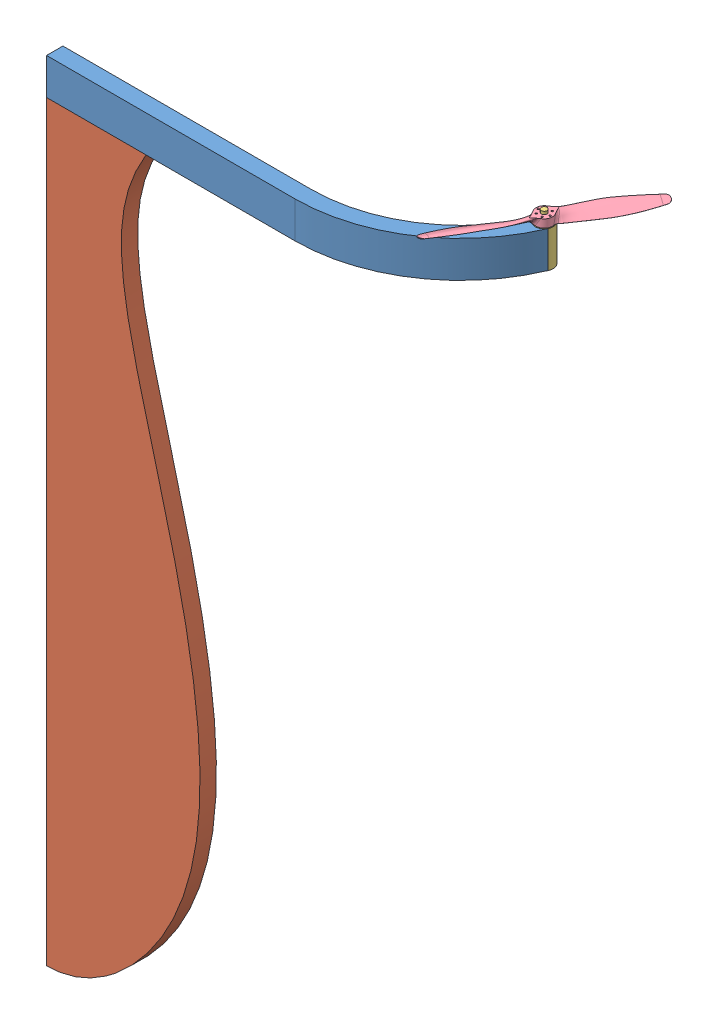
SolidWorks assembly sym, configuration Default. Lengths in mm.
Overall size (867.99 256.75 952.37).
6 component instances, 4 part files, 2 mates.
Components (placement in the parent):
- bodysym-1: bodysym [Default] at (-16.2495 216.5456 2.6479) size (110.04 216.55 28.06)
  - mp-1: mp [Default] at (9.9204 70.4329 1.4803) size (110.04 10 28.06)
  - plade 2-1: plade 2 [Default] at (-8.8992 -21.1842 13.0421) x (0 -1 0) z (0 0 -1) size (206.55 46.77 4.49)
- motorsym-1: motorsym [Default] at (69.1428 286.9784 -66.2088) x (-0.6324 0 0.774642) z (-0.774642 0 -0.6324) size (950.73 131.02 344.34)
  - motor-1: motor [Default] at (56.1749 10 -15.5304) x (-0.204409 0 -0.978885) z (0.978885 0 -0.204409) size (4.92 13 4.92)
  - propeller-1: propeller [Default] at (54.4283 1.9853 -17.262) x (0.987389 0 -0.158315) z (0.158315 0 0.987389) size (939.94 131.02 198.03)
Mates (geometry in assembly coordinates):
- Concentric2: concentric anti-aligned: cylinder of bodysym-1/mp-1 through (48.0958 296.9784 -13.133) axis (0 -1 0) radius 2.4614; cylinder of motorsym-1/motor-1 through (48.0958 286.9784 -13.133) axis (0 1 0) radius 2.4614
- Coincident1: coincident aligned: circle of bodysym-1/mp-1; circle of motorsym-1/motor-1
